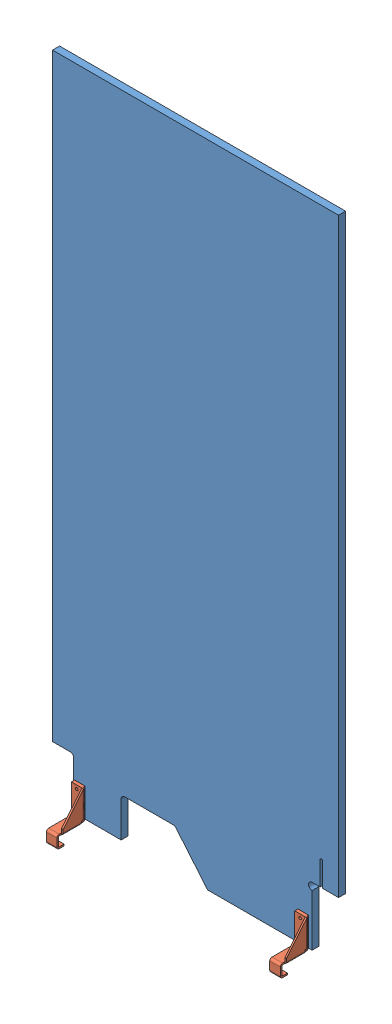
SolidWorks assembly 190217_GenericPlayfield_6, configuration Default. Lengths in mm.
Overall size (514.35 1190.94 63.5).
3 component instances, 2 part files, 6 mates.
Components (placement in the parent):
- 190217_GenericPlayfield_6-1: 190217_GenericPlayfield_6 [Default] at (-10601.4435 -13603.702 6.35) size (514.35 1168.4 12.7)
- 190216_HangerBracket_1-1: 190216_HangerBracket_1 [Default] at (-204.906 -227.7444 -781.05) x (0 -1 0) z (-1 0 0) size (74.1 50.8 21.97)
- 190216_HangerBracket_1-2: 190216_HangerBracket_1 [Default] at (196.7315 -227.7444 -781.05) x (0 -1 0) z (-1 0 0) size (74.1 50.8 21.97)
Mates (geometry in assembly coordinates):
- Concentric1: concentric anti-aligned: circle of 190217_GenericPlayfield_6-1; circle of 190216_HangerBracket_1-1
- Coincident1: coincident anti-aligned: plane of 190217_GenericPlayfield_6-1 through (-231.8914 -501.049 6.35) normal (0 0 1); plane of 190216_HangerBracket_1-1 through (-223.956 -534.6399 6.35) normal (0 0 -1)
- Parallel1: parallel aligned: plane of 190217_GenericPlayfield_6-1 through (-140.2407 -586.2019 -6.35) normal (0 -1 0); plane of 190216_HangerBracket_1-1 through (-223.956 -588.9959 11.176) normal (0 -1 0)
- Concentric2: concentric: circle of 190217_GenericPlayfield_6-1; circle of ?
- Coincident3: coincident: plane of 190217_GenericPlayfield_6-1 through (-231.8914 -501.049 6.35) normal (0 0 1); plane of ? through (162.9095 -543.8412 6.35) normal (0 0 -1)
- Parallel2: parallel aligned: plane of ?; plane of ?
